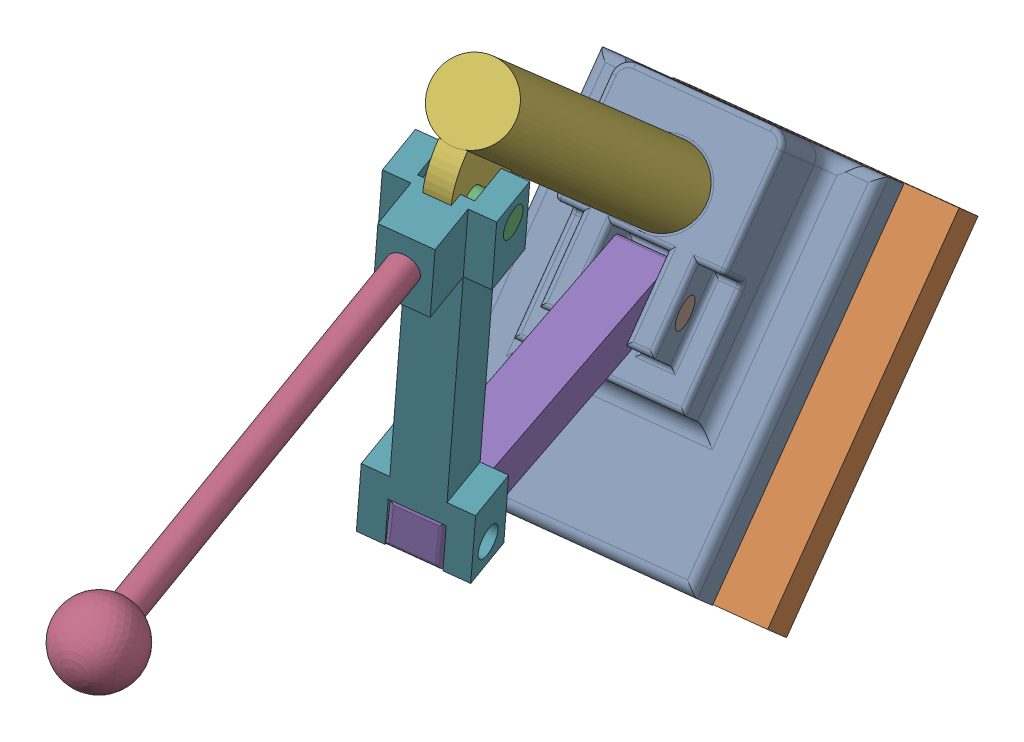
SolidWorks assembly press 2, configuration Varsayılan. Lengths in mm.
Overall size (281.36 411.01 635.16).
8 component instances, 7 part files, 16 mates.
Components (placement in the parent):
- upperbase-1: upperbase [Default] at (-11.0816 -324.6092 201.1522) x (0.952185 -0.142237 -0.270394) z (0.295836 0.650326 0.699684) size (127 177.8 76.2)
- lowerbase-1: lowerbase [Default] at (-101.5703 -437.0316 201.6083) x (0.952185 -0.142237 -0.270394) z (0.295836 0.650326 0.699684) size (127 177.8 25.4)
- pin2-1: pin2 [Default] at (94.1688 -110.6999 390.4566) x (0.28262 0.073864 0.956384) z (-0.952185 0.142237 0.270394) size (15.24 15.24 50.8)
- handle-1: handle [Default] at (136.7481 -153.1513 658.1037) x (0.929659 -0.23971 -0.279773) z (0.249338 -0.149685 0.956778) size (40.64 40.64 274.32)
- link1-1: link1 [Default] at (35.1267 -285.438 321.4287) x (-0.16253 -0.98522 -0.054083) z (-0.952185 0.142237 0.270394) size (25.4 177.8 25.4)
- verticalsupport-1: verticalsupport [Default] at (75.973 -61.0059 394.1769) x (0.076323 -0.74622 0.661309) z (0.295836 0.650326 0.699684) size (66.82 38.1 431.8)
- link2-1: link2 [Default] at (68.4106 -160.1102 372.71) x (-0.249338 0.149685 -0.956778) z (0.952185 -0.142237 -0.270394) size (50.8 203.2 50.8)
- pin2-2: pin2 [Default] at (23.8293 -270.4106 226.7715) x (0.28262 0.073864 0.956384) z (-0.952185 0.142237 0.270394) size (15.24 15.24 50.8)
Mates (geometry in assembly coordinates):
- Eş Merkezli1: concentric aligned: cylinder of upperbase-1 through (-26.3345 -285.905 152.2086) axis (0.295836 0.650326 0.699684) radius 17.6968; cylinder of verticalsupport-1 through (-51.769 -341.8166 92.0534) axis (0.295836 0.650326 0.699684) radius 19.05
- Eş Merkezli2: concentric aligned: circle of lowerbase-1; cylinder of verticalsupport-1 through (-51.769 -341.8166 92.0534) axis (0.295836 0.650326 0.699684) radius 19.05
- Çakışık2: coincident aligned: plane of lowerbase-1 through (-115.1406 -304.3536 84.0275) normal (-0.295836 -0.650326 -0.699684); plane of verticalsupport-1 through (-51.769 -341.8166 92.0534) normal (-0.295836 -0.650326 -0.699684)
- Eş Merkezli5: concentric anti-aligned: circle of verticalsupport-1; circle of link2-1
- Eş Merkezli6: concentric anti-aligned: circle of verticalsupport-1; circle of link2-1
- Genişlik1: width anti-aligned: plane of link2-1 through (99.8395 -99.4134 404.4889) normal (0.952185 -0.142237 -0.270394); plane of verticalsupport-1 through (51.4685 -92.1877 418.225) normal (-0.952185 0.142237 0.270394); plane of link2-1 through (62.5799 -92.9161 387.2835) normal (-0.952185 0.142237 0.270394); plane of verticalsupport-1 through (74.6726 -94.7225 383.8495) normal (0.952185 -0.142237 -0.270394)
- Eş Merkezli7: concentric aligned: cylinder of handle-1 through (73.7021 -114.0027 415.4951) axis (0.259869 -0.088344 0.961594) radius 7.62; cylinder of link2-1 through (73.7021 -114.0027 415.4951) axis (0.259869 -0.088344 0.961594) radius 7.62
- Eş Merkezli8: concentric anti-aligned: cylinder of pin2-1 through (45.7978 -103.4743 404.1926) axis (0.952185 -0.142237 -0.270394) radius 7.62; cylinder of link2-1 through (94.1688 -110.6999 390.4566) axis (-0.952185 0.142237 0.270394) radius 7.62
- Çakışık12: coincident anti-aligned: circle of pin2-1; plane of link2-1 through (99.8395 -99.4134 404.4889) normal (0.952185 -0.142237 -0.270394)
- Çakışık13: coincident aligned: circle of link1-1; circle of link2-1
- Eş Merkezli9: concentric aligned: cylinder of link1-1 through (104.8002 -291.9404 372.9346) axis (-0.952185 0.142237 0.270394) radius 7.62; cylinder of link2-1 through (66.1034 -286.1599 383.9234) axis (-0.952185 0.142237 0.270394) radius 7.62
- Eş Merkezli10: concentric aligned: cylinder of upperbase-1 through (38.501 -260.8699 235.844) axis (-0.952185 0.142237 0.270394) radius 7.62; cylinder of link1-1 through (67.5236 -265.2053 227.6024) axis (-0.952185 0.142237 0.270394) radius 7.62
- Çakışık14: coincident anti-aligned: circle of upperbase-1; cylinder of pin2-2 through (-10.6466 -232.6398 273.371) axis (0.952185 -0.142237 -0.270394) radius 7.62
- Çakışık15: coincident anti-aligned: plane of upperbase-1 through (31.1129 -236.7834 234.7315) normal (0.952185 -0.142237 -0.270394); circle of pin2-2
- Çakışık16: coincident anti-aligned: plane of handle-1; plane of link2-1
- Çakışık17: coincident aligned: plane of upperbase-1 through (-78.1724 -223.0876 171.4614) normal (-0.952185 0.142237 0.270394); plane of lowerbase-1 through (-94.0561 -420.5133 219.3803) normal (-0.952185 0.142237 0.270394)
